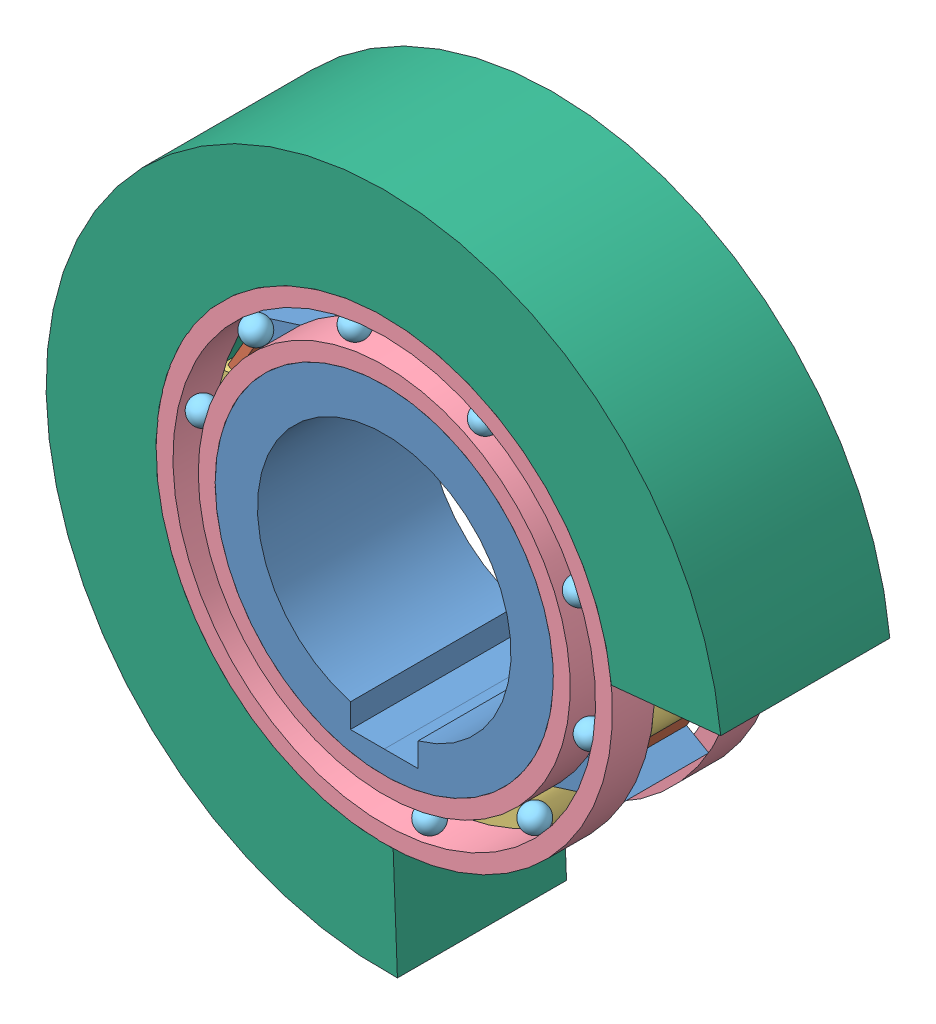
SolidWorks assembly Assem3, configuration Default. Lengths in mm.
Overall size (103.47 104.97 21.66).
38 component instances, 6 part files, 47 mates.
Components (placement in the parent):
- Part4-1: Part4 [Default] at (17.8749 31.9855 30.0684) size (46.77 54 20)
- Part7-1: Part7 [Default] at (13.3618 54.8249 35.0684) size (5 1 10)
- Part6-1: Part6 [Default] at (9.3749 53.8944 35.0684) x (-0.170676 -0.985327 0) z (0 0 1) size (7 7 10)
- Part7-2: Part7 [Default] at (-4.6283 39.7664 35.0684) x (0.5 0.866025 0) z (0 0 1) size (5 1 10)
- Part7-3: Part7 [Default] at (18.3618 9.0949 35.0684) size (5 1 10)
- Part7-4: Part7 [Default] at (0.4837 16.7335 35.0684) x (-0.5 0.866025 0) z (0 0 1) size (5 1 10)
- Part7-5: Part7 [Default] at (35.618 47.4408 35.0684) x (0.5 -0.866025 0) z (0 0 1) size (5 1 10)
- Part7-6: Part7 [Default] at (40.1391 24.3425 35.0684) x (-0.5 -0.866025 0) z (0 0 1) size (5 1 10)
- Part6-2: Part6 [Default] at (26.3749 9.8666 35.0684) x (0.623953 0.781462 0) z (0 0 1) size (7 7 10)
- Part6-3: Part6 [Default] at (3.1512 13.6698 35.0684) x (0.999 -0.044706 0) z (0 0 1) size (7 7 10)
- Part6-4: Part6 [Default] at (-5.3488 35.5788 35.0684) x (0.887185 -0.461414 0) z (0 0 1) size (7 7 10)
- Part6-5: Part6 [Default] at (32.5985 50.3012 35.0684) x (0.177855 0.984057 0) z (0 0 1) size (7 7 10)
- Part6-6: Part6 [Default] at (41.0985 28.3923 35.0684) x (0.558893 -0.82924 0) z (0 0 1) size (7 7 10)
- Assem1-1: Assem1 [Default] at (48.9165 51.5334 7.3784) x (-0.863071 0.505083 0) z (0 0 1) size (54 54 6.66)
  - part1-1: part1 [Default] at (16.9178 32.5498 37.6901) size (54 54 5)
  - Part2-1: Part2 [Default] at (15.7988 56.0232 39.1901) x (0.695893 -0.715494 0.061661) z (-0.608878 -0.542305 0.57894) size (3 3 3)
  - Part2-3: Part2 [Default] at (30.7603 51.5402 39.1901) x (0.103388 0.325469 -0.939884) z (-0.992295 -0.031114 -0.119927) size (3 3 3)
  - Part2-4: Part2 [Default] at (39.3087 39.6842 41.1901) x (-0.310301 -0.537174 -0.784319) z (0.92301 0.027217 -0.383812) size (3 3 3)
  - Part2-5: Part2 [Default] at (-5.7008 38.9254 41.1901) x (0.936185 -0.169832 -0.307758) z (0.32567 0.089599 0.941229) size (3 3 3)
  - Part2-6: Part2 [Default] at (32.8009 15.23 41.1901) x (0.614183 0.637295 -0.46544) z (-0.140496 -0.492065 -0.859147) size (3 3 3)
  - Part2-8: Part2 [Default] at (18.521 9.1046 41.1901) x (-0.315573 -0.348284 -0.882673) z (-0.47525 0.86314 -0.170665) size (3 3 3)
  - Part2-10: Part2 [Default] at (1.8711 50.601 41.1901) x (0.948163 0.311723 0.061777) z (-0.081665 0.051141 0.995347) size (3 3 3)
  - Part2-11: Part2 [Default] at (39.6779 26.6993 41.1901) x (0.946732 0.243084 -0.211208) z (-0.04215 0.74378 0.667094) size (3 3 3)
  - Part2-12: Part2 [Default] at (-5.4262 25.2699 41.1901) x (0.902415 -0.200103 0.381583) z (-0.429183 -0.339219 0.837098) size (3 3 3)
  - Part2-13: Part2 [Default] at (2.7917 13.7694 41.1901) x (0.827852 0.035551 0.559819) z (-0.550532 -0.139921 0.823004) size (3 3 3)
- Assem1-2: Assem1 [Default] at (50.4071 48.9372 -7.6216) x (-0.819012 0.573776 0) z (0 0 1) size (54 54 6.66)
  - part1-1: part1 [Default] at (16.9178 32.5498 37.6901) size (54 54 5)
  - Part2-1: Part2 [Default] at (15.7988 56.0232 39.1901) x (0.695893 -0.715494 0.061661) z (-0.608878 -0.542305 0.57894) size (3 3 3)
  - Part2-3: Part2 [Default] at (30.7603 51.5402 39.1901) x (0.103388 0.325469 -0.939884) z (-0.992295 -0.031114 -0.119927) size (3 3 3)
  - Part2-4: Part2 [Default] at (39.3087 39.6842 41.1901) x (-0.310301 -0.537174 -0.784319) z (0.92301 0.027217 -0.383812) size (3 3 3)
  - Part2-5: Part2 [Default] at (-5.7008 38.9254 41.1901) x (0.936185 -0.169832 -0.307758) z (0.32567 0.089599 0.941229) size (3 3 3)
  - Part2-6: Part2 [Default] at (32.8009 15.23 41.1901) x (0.614183 0.637295 -0.46544) z (-0.140496 -0.492065 -0.859147) size (3 3 3)
  - Part2-8: Part2 [Default] at (18.521 9.1046 41.1901) x (-0.315573 -0.348284 -0.882673) z (-0.47525 0.86314 -0.170665) size (3 3 3)
  - Part2-10: Part2 [Default] at (1.8711 50.601 41.1901) x (0.948163 0.311723 0.061777) z (-0.081665 0.051141 0.995347) size (3 3 3)
  - Part2-11: Part2 [Default] at (39.6779 26.6993 41.1901) x (0.946732 0.243084 -0.211208) z (-0.04215 0.74378 0.667094) size (3 3 3)
  - Part2-12: Part2 [Default] at (-5.4262 25.2699 41.1901) x (0.902415 -0.200103 0.381583) z (-0.429183 -0.339219 0.837098) size (3 3 3)
  - Part2-13: Part2 [Default] at (2.7917 13.7694 41.1901) x (0.827852 0.035551 0.559819) z (-0.550532 -0.139921 0.823004) size (3 3 3)
- Part5-1: Part5 [Default] at (17.8749 31.9855 30.0684) x (-0.642298 -0.766455 0) z (0 0 1) size (80 67.96 20)
Mates (geometry in assembly coordinates):
- Coincident1: coincident anti-aligned: plane of Part4-1 through (17.8749 31.9855 45.0684) normal (-1 0 0); plane of Part7-1 through (17.8749 55.7 45.0684) normal (1 0 0)
- Coincident2: coincident aligned: plane of Part4-1 through (17.8749 31.9855 35.0684) normal (0 0 -1); plane of Part7-1 through (13.3618 54.8249 35.0684) normal (0 0 -1)
- Tangent1: tangent anti-aligned: plane of Part7-1 through (12.8749 55.7 45.0684) normal (-1 0 0); cylinder of Part6-1 through (9.3749 53.8944 45.0684) axis (0 0 -1) radius 3.5
- Tangent2: tangent anti-aligned: cylinder of Part4-1 through (17.8749 31.9855 50.0684) axis (0 0 -1) radius 20; cylinder of Part6-1 through (9.3749 53.8944 45.0684) axis (0 0 -1) radius 3.5
- Coincident3: coincident anti-aligned: plane of Part4-1 through (17.8749 31.9855 45.0684) normal (-0.5 -0.866025 0); plane of Part7-2 through (-3.1296 44.1124 45.0684) normal (0.5 0.866025 0)
- Coincident4: coincident aligned: plane of Part4-1 through (17.8749 31.9855 35.0684) normal (0 0 -1); plane of Part7-2 through (-4.6283 39.7664 35.0684) normal (0 0 -1)
- Lock1: lock: unknown of Part4-1; unknown of Part7-2
- Coincident6: coincident anti-aligned: plane of Part4-1 through (17.8749 31.9855 45.0684) normal (-0.5 0.866025 0); plane of Part7-5 through (38.6324 43.9699 45.0684) normal (0.5 -0.866025 0)
- Coincident7: coincident aligned: plane of Part4-1 through (17.8749 31.9855 35.0684) normal (0 0 -1); plane of Part7-5 through (35.618 47.4408 35.0684) normal (0 0 -1)
- Lock2: lock: unknown of Part4-1; unknown of Part7-5
- Coincident9: coincident anti-aligned: plane of Part7-1 through (13.3618 54.8249 35.0684) normal (0 0 -1); circle of Part6-1
- Coincident10: coincident anti-aligned: plane of Part4-1 through (17.8749 31.9855 45.0684) normal (0.5 0.866025 0); plane of Part7-6 through (38.6404 19.9965 45.0684) normal (-0.5 -0.866025 0)
- Coincident13: coincident aligned: plane of Part4-1 through (17.8749 31.9855 35.0684) normal (0 0 -1); plane of Part7-6 through (40.1391 24.3425 35.0684) normal (0 0 -1)
- Lock3: lock: unknown of Part4-1; unknown of Part7-6
- Coincident15: coincident: plane of Part4-1 through (17.8749 31.9855 45.0684) normal (1 0 0); line of Part7-3 through (17.8749 9.97 45.0684) axis (0 0 -1)
- Coincident16: coincident aligned: plane of Part4-1 through (17.8749 31.9855 45.0684) normal (0 0 1); plane of Part7-3 through (18.3618 9.0949 45.0684) normal (0 0 1)
- Lock4: lock: unknown of Part4-1; unknown of Part7-3
- Coincident18: coincident anti-aligned: plane of Part4-1 through (17.8749 31.9855 45.0684) normal (0.5 -0.866025 0); plane of Part7-4 through (-2.5307 20.2044 45.0684) normal (-0.5 0.866025 0)
- Coincident19: coincident aligned: plane of Part4-1 through (17.8749 31.9855 35.0684) normal (0 0 -1); plane of Part7-4 through (0.4837 16.7335 35.0684) normal (0 0 -1)
- Lock5: lock: unknown of Part4-1; unknown of Part7-4
- Tangent3: tangent anti-aligned: cylinder of Part4-1 through (17.8749 31.9855 50.0684) axis (0 0 -1) radius 20; cylinder of Part6-6 through (41.0985 28.3923 45.0684) axis (0 0 -1) radius 3.5
- Coincident21: coincident aligned: plane of Part7-6 through (40.1391 24.3425 35.0684) normal (0 0 -1); plane of Part6-6 through (41.0985 28.3923 35.0684) normal (0 0 -1)
- Tangent4: tangent anti-aligned: plane of Part7-6 through (41.1404 24.3267 45.0684) normal (0.5 0.866025 0); cylinder of Part6-6 through (41.0985 28.3923 45.0684) axis (0 0 -1) radius 3.5
- Tangent5: tangent anti-aligned: cylinder of Part4-1 through (17.8749 31.9855 50.0684) axis (0 0 -1) radius 20; cylinder of Part6-5 through (32.5985 50.3012 45.0684) axis (0 0 -1) radius 3.5
- Coincident22: coincident aligned: plane of Part7-5 through (35.618 47.4408 35.0684) normal (0 0 -1); plane of Part6-5 through (32.5985 50.3012 35.0684) normal (0 0 -1)
- Tangent6: tangent anti-aligned: plane of Part7-5 through (36.1324 48.3 45.0684) normal (-0.5 0.866025 0); cylinder of Part6-5 through (32.5985 50.3012 45.0684) axis (0 0 -1) radius 3.5
- Coincident23: coincident aligned: plane of Part7-3 through (18.3618 9.0949 35.0684) normal (0 0 -1); plane of Part6-2 through (26.3749 9.8666 35.0684) normal (0 0 -1)
- Tangent7: tangent anti-aligned: plane of Part7-3 through (22.8749 9.97 45.0684) normal (1 0 0); cylinder of Part6-2 through (26.3749 9.8666 45.0684) axis (0 0 -1) radius 3.5
- Parallel1: parallel aligned: cylinder of Part4-1 through (17.8749 31.9855 50.0684) axis (0 0 -1) radius 20; cylinder of Part6-2 through (26.3749 9.8666 45.0684) axis (0 0 -1) radius 3.5
- Tangent8: tangent anti-aligned: plane of Part7-3 through (22.8749 9.97 45.0684) normal (1 0 0); cylinder of Part6-2 through (26.3749 9.8666 45.0684) axis (0 0 -1) radius 3.5
- Lock6: lock: unknown of Part7-3; unknown of Part6-2
- Coincident25: coincident aligned: plane of Part7-4 through (0.4837 16.7335 45.0684) normal (0 0 1); plane of Part6-3 through (3.1512 13.6698 45.0684) normal (0 0 1)
- Tangent9: tangent anti-aligned: cylinder of Part4-1 through (17.8749 31.9855 50.0684) axis (0 0 -1) radius 20; cylinder of Part6-3 through (3.1512 13.6698 45.0684) axis (0 0 -1) radius 3.5
- Coincident26: coincident aligned: plane of Part7-4 through (0.4837 16.7335 45.0684) normal (0 0 1); plane of Part6-3 through (3.1512 13.6698 45.0684) normal (0 0 1)
- Tangent10: tangent anti-aligned: plane of Part7-4 through (-0.0307 15.8743 45.0684) normal (0.5 -0.866025 0); cylinder of Part6-3 through (3.1512 13.6698 45.0684) axis (0 0 -1) radius 3.5
- Coincident27: coincident aligned: plane of Part7-2 through (-4.6283 39.7664 45.0684) normal (0 0 1); plane of Part6-4 through (-5.3488 35.5788 45.0684) normal (0 0 1)
- Tangent11: tangent anti-aligned: plane of Part7-2 through (-5.6296 39.7823 45.0684) normal (-0.5 -0.866025 0); cylinder of Part6-4 through (-5.3488 35.5788 45.0684) axis (0 0 -1) radius 3.5
- Tangent12: tangent anti-aligned: cylinder of Part4-1 through (17.8749 31.9855 50.0684) axis (0 0 -1) radius 20; cylinder of Part6-4 through (-5.3488 35.5788 45.0684) axis (0 0 -1) radius 3.5
- Coincident28: coincident aligned: plane of Part4-1 through (17.8749 31.9855 50.0684) normal (0 0 1); plane of Assem1-1/part1-1 through (17.8749 31.9855 50.0684) normal (0 0 1)
- Concentric10: concentric aligned: cylinder of Part4-1 through (17.8749 31.9855 50.0684) axis (0 0 -1) radius 20; cylinder of Assem1-1/part1-1 through (17.8749 31.9855 50.0684) axis (0 0 -1) radius 20
- Coincident29: coincident aligned: plane of Part4-1 through (17.8749 31.9855 30.0684) normal (0 0 -1); plane of Assem1-2/part1-1 through (17.8749 31.9855 30.0684) normal (0 0 -1)
- Concentric11: concentric aligned: cylinder of Part4-1 through (17.8749 31.9855 50.0684) axis (0 0 -1) radius 15; cylinder of Assem1-2/part1-1 through (17.8749 31.9855 35.0684) axis (0 0 -1) radius 20
- Concentric12: concentric aligned: cylinder of Assem1-1/part1-1 through (17.8749 31.9855 50.0684) axis (0 0 -1) radius 27; cylinder of Assem1-2/part1-1 through (17.8749 31.9855 35.0684) axis (0 0 -1) radius 27
- Parallel3: parallel aligned: cylinder of Assem1-1/part1-1 through (17.8749 31.9855 50.0684) axis (0 0 -1) radius 27; cylinder of Assem1-2/part1-1 through (17.8749 31.9855 35.0684) axis (0 0 -1) radius 27
- Lock8: lock: unknown of ?; unknown of ?
- Concentric16: concentric aligned: cylinder of Assem1-1/part1-1 through (17.8749 31.9855 50.0684) axis (0 0 -1) radius 27; cylinder of Part5-1 through (17.8749 31.9855 50.0684) axis (0 0 -1) radius 27
- Coincident30: coincident aligned: plane of Assem1-2/part1-1 through (17.8749 31.9855 30.0684) normal (0 0 -1); plane of Part5-1 through (17.8749 31.9855 30.0684) normal (0 0 -1)
